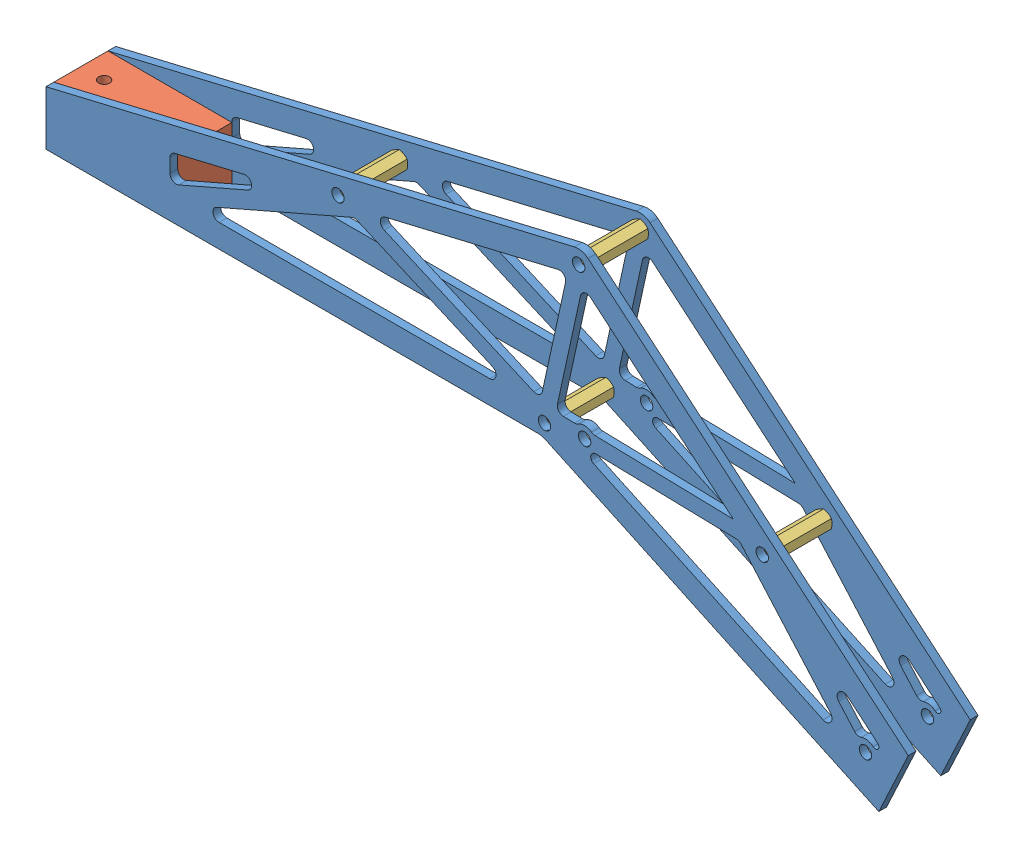
SolidWorks assembly MBMechanicalTrussCoupler, configuration Default. Lengths in mm.
Overall size (353.4 138.23 28.68).
7 component instances, 3 part files, 14 mates.
Components (placement in the parent):
- MBTrussSide-1: MBTrussSide [Default] at origin size (353.4 138.23 3.28)
- MBTrussSide-2: MBTrussSide [Default] at (0 0 25.4) size (353.4 138.23 3.28)
- MBMechanicalTrussShaftCoupler-1: MBMechanicalTrussShaftCoupler [Default] at (-152.4 11.1125 14.2875) x (0 0 1) z (-1 0 0) size (22.23 22.23 50.8)
- 91115A144_18-8 SS FEM THRDED HEX STANDOFF-1: 91115A144_18-8 SS FEM THRDED HEX STANDOFF [91115A144] at (15.1183 68.1943 14.2875) size (6.35 7.33 22.9)
- 91115A144_18-8 SS FEM THRDED HEX STANDOFF-2: 91115A144_18-8 SS FEM THRDED HEX STANDOFF [91115A144] at (-83.538 43.5026 14.2875) size (6.35 7.33 22.9)
- 91115A144_18-8 SS FEM THRDED HEX STANDOFF-3: 91115A144_18-8 SS FEM THRDED HEX STANDOFF [91115A144] at (90.3519 2.8875 14.2875) size (6.35 7.33 22.9)
- 91115A144_18-8 SS FEM THRDED HEX STANDOFF-4: 91115A144_18-8 SS FEM THRDED HEX STANDOFF [91115A144] at (1.0995 4.9596 14.2875) size (6.35 7.33 22.9)
Mates (geometry in assembly coordinates):
- Coincident1: coincident anti-aligned: plane of MBTrussSide-1 through (0 0 3.175) normal (0 0 1); plane of MBMechanicalTrussShaftCoupler-1 through (-203.2 22.225 3.175) normal (0 0 -1)
- Coincident2: coincident anti-aligned: plane of MBTrussSide-2 through (0 0 25.4) normal (0 0 -1); plane of MBMechanicalTrussShaftCoupler-1 through (-203.2 22.225 25.4) normal (0 0 1)
- Coincident3: coincident aligned: plane of MBTrussSide-1 through (-203.2 0 3.175) normal (-1 0 0); plane of MBMechanicalTrussShaftCoupler-1 through (-203.2 11.1125 14.2875) normal (-1 0 0)
- Coincident4: coincident aligned: plane of MBTrussSide-2 through (-203.2 0 28.575) normal (-1 0 0); plane of MBMechanicalTrussShaftCoupler-1 through (-203.2 11.1125 14.2875) normal (-1 0 0)
- Coincident5: coincident aligned: plane of MBTrussSide-1 through (0 0 3.175) normal (0 -1 0); plane of MBMechanicalTrussShaftCoupler-1 through (-203.2 0 3.175) normal (0 -1 0)
- Coincident6: coincident aligned: plane of MBTrussSide-2 through (0 0 28.575) normal (0 -1 0); plane of MBMechanicalTrussShaftCoupler-1 through (-203.2 0 3.175) normal (0 -1 0)
- Concentric1: concentric anti-aligned: circle of MBTrussSide-2; circle of 91115A144_18-8 SS FEM THRDED HEX STANDOFF-1
- Concentric2: concentric anti-aligned: cylinder of MBTrussSide-2 through (-83.538 43.5026 28.575) axis (0 0 1) radius 2.5527; circle of 91115A144_18-8 SS FEM THRDED HEX STANDOFF-2
- Concentric3: concentric anti-aligned: cylinder of MBTrussSide-2 through (1.0995 4.9596 28.575) axis (0 0 1) radius 2.5527; circle of 91115A144_18-8 SS FEM THRDED HEX STANDOFF-4
- Concentric4: concentric aligned: cylinder of MBTrussSide-2 through (90.3519 2.8875 28.575) axis (0 0 1) radius 2.5527; cone of 91115A144_18-8 SS FEM THRDED HEX STANDOFF-3 through (90.3519 2.8875 25.4) axis (0 0 1)
- Coincident8: coincident anti-aligned: plane of MBTrussSide-2 through (0 0 25.4) normal (0 0 -1); plane of 91115A144_18-8 SS FEM THRDED HEX STANDOFF-3 through (90.3519 6.5537 25.4) normal (0 0 1)
- Coincident9: coincident anti-aligned: plane of MBTrussSide-2 through (0 0 25.4) normal (0 0 -1); plane of 91115A144_18-8 SS FEM THRDED HEX STANDOFF-1 through (15.1183 71.8605 25.4) normal (0 0 1)
- Coincident10: coincident anti-aligned: plane of MBTrussSide-2 through (0 0 25.4) normal (0 0 -1); plane of 91115A144_18-8 SS FEM THRDED HEX STANDOFF-4 through (1.0995 8.6258 25.4) normal (0 0 1)
- Coincident11: coincident anti-aligned: plane of MBTrussSide-2 through (0 0 25.4) normal (0 0 -1); plane of 91115A144_18-8 SS FEM THRDED HEX STANDOFF-2 through (-83.538 47.1688 25.4) normal (0 0 1)
